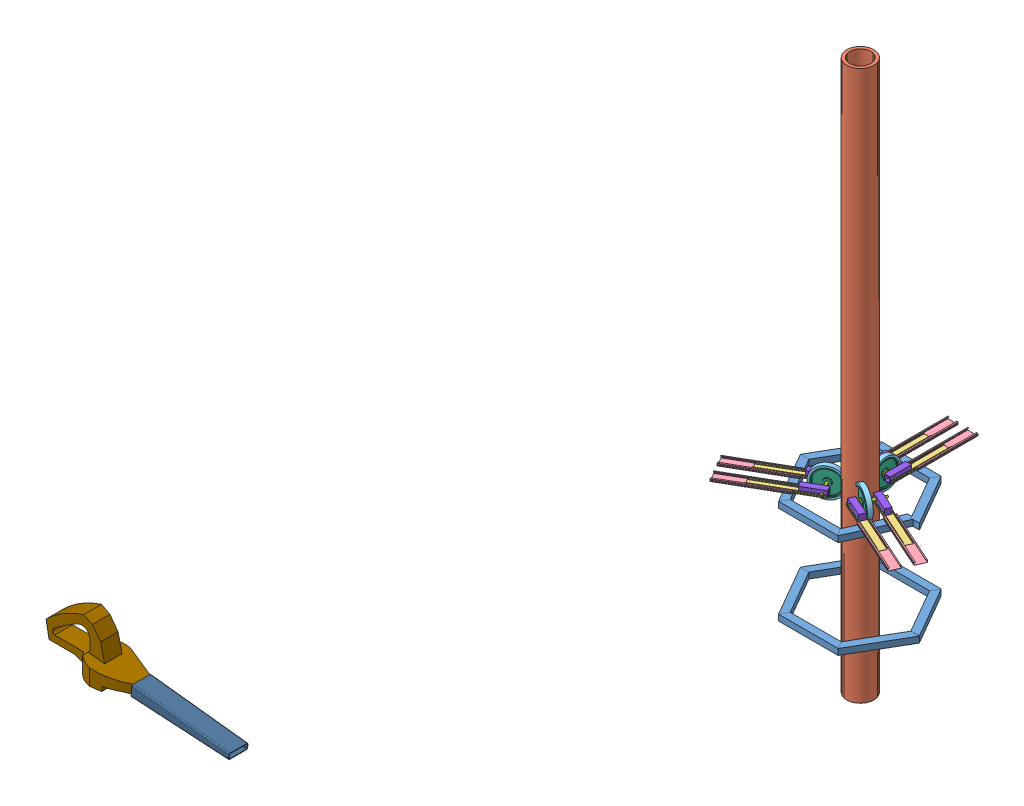
SolidWorks assembly hybrid_new, configuration Default. Lengths in mm.
Overall size (2085.21 2307.62 2779.85).
55 component instances, 10 part files, 44 mates.
Components (placement in the parent):
- Part1-1: Part1 [Default] at (62.7195 89.3412 215.5234) size (250 25.4 31.11)
- Part1-2: Part1 [Default] at (-99.5841 89.3412 82.0449) x (0.5 0 0.866025) z (-0.866025 0 0.5) size (250 25.4 31.11)
- Part1-3: Part1 [Default] at (62.7195 -320.6588 215.5234) size (250 25.4 31.11)
- Part1-4: Part1 [Default] at (250.7642 89.3412 138.3186) x (0.408641 0 -0.912695) z (0.912695 0 0.408641) size (250 25.4 31.11)
- Part1-5: Part1 [Default] at (293.911 -320.6588 -65.5947) x (-0.5 0 -0.866025) z (0.866025 0 -0.5) size (250 25.4 31.11)
- Part1-6: Part1 [Default] at (-65.1402 -320.6588 -125.2534) x (-0.5 0 0.866025) z (-0.866025 0 -0.5) size (250 25.4 31.11)
- Part1-7: Part1 [Default] at (259.7705 -320.6588 141.8405) x (0.503164 0 -0.864191) z (0.864191 0 0.503164) size (250 25.4 31.11)
- Part1-8: Part1 [Default] at (293.911 89.3412 -65.5947) x (-0.5 0 -0.866025) z (0.866025 0 -0.5) size (250 25.4 31.11)
- Part1-9: Part1 [Default] at (131.6074 -320.6588 -199.0732) x (-1 0 0) z (0 0 -1) size (250 25.4 31.11)
- Part1-10: Part1 [Default] at (-65.1402 89.3412 -125.2534) x (-0.5 0 0.866025) z (-0.866025 0 -0.5) size (250 25.4 31.11)
- Part1-11: Part1 [Default] at (131.6074 89.3412 -199.0732) x (-1 0 0) z (0 0 -1) size (250 25.4 31.11)
- Part1-12: Part1 [Default] at (-99.5841 -320.6588 82.0449) x (0.5 0 0.866025) z (-0.866025 0 0.5) size (250 25.4 31.11)
- pole-1: pole [Default] at (101.3065 -621.7615 10.6171) x (-0.949748 0 0.313015) z (-0.313015 0 -0.949748) size (114 2307.62 114)
- wheel_sys-1: wheel_sys [Default] at (-216.3042 -39.4819 -61.3313) x (0 0 -1) z (1 0 0) size (427.17 170.74 131.58)
  - slider-1: slider [Default] at (295.7545 161.9821 248.2331) size (359 10.5 44.88)
    - inner slider-1: inner slider [Default] at (-151.895 -7.559 16.8408) size (254 10.3 34.88)
    - outer slider-1: outer slider [Default] at (-46.895 -7.759 16.5388) size (254 10.08 44.88)
  - wheelwithaxle-1: wheelwithaxle [Default] at (804.7391 46.5563 384.5567) x (0.829197 -0.558957 0) z (-0.558957 -0.829197 0) size (123 127 123)
    - rim-1: rim [Default] at (-711.4248 -76.2879 334.1654) size (123 19 123)
    - centre-1: centre [Default] at (-711.4248 -76.2879 334.1654) size (107 19 107)
    - wheel axle-1: wheel axle [Default] at (-713.6031 -81.7741 334.1654) size (28 127 28)
  - slider-2: slider [Default] at (295.7545 161.9821 330.8673) size (359 10.5 44.88)
    - inner slider-1: inner slider [Default] at (-151.895 -7.559 16.8408) size (254 10.3 34.88)
    - outer slider-1: outer slider [Default] at (-46.895 -7.759 16.5388) size (254 10.08 44.88)
  - support-1: support [Default] at (-18.9561 167.1231 347.1618) x (0 -1 0) z (0 0 1) size (25 90.2 25)
  - support-2: support [Default] at (-18.9561 167.1231 265.119) x (0 -1 0) z (0 0 1) size (25 90.2 25)
- wheel_sys-2: wheel_sys [Default] at (198.0796 -39.4819 322.1299) x (-0.866025 0 0.5) z (-0.5 0 -0.866025) size (427.17 170.74 131.58)
  - slider-1: slider [Default] at (295.7545 161.9821 248.2331) size (359 10.5 44.88)
    - inner slider-1: inner slider [Default] at (-151.895 -7.559 16.8408) size (254 10.3 34.88)
    - outer slider-1: outer slider [Default] at (-46.895 -7.759 16.5388) size (254 10.08 44.88)
  - wheelwithaxle-1: wheelwithaxle [Default] at (804.7391 46.5563 384.5567) x (0.829197 -0.558957 0) z (-0.558957 -0.829197 0) size (123 127 123)
    - rim-1: rim [Default] at (-711.4248 -76.2879 334.1654) size (123 19 123)
    - centre-1: centre [Default] at (-711.4248 -76.2879 334.1654) size (107 19 107)
    - wheel axle-1: wheel axle [Default] at (-713.6031 -81.7741 334.1654) size (28 127 28)
  - slider-2: slider [Default] at (295.7545 161.9821 330.8673) size (359 10.5 44.88)
    - inner slider-1: inner slider [Default] at (-151.895 -7.559 16.8408) size (254 10.3 34.88)
    - outer slider-1: outer slider [Default] at (-46.895 -7.759 16.5388) size (254 10.08 44.88)
  - support-1: support [Default] at (-18.9561 167.1231 347.1618) x (0 -1 0) z (0 0 1) size (25 90.2 25)
  - support-2: support [Default] at (-18.9561 167.1231 265.119) x (0 -1 0) z (0 0 1) size (25 90.2 25)
- wheel_sys-3: wheel_sys [Default] at (268.6929 -39.4819 -238.7978) x (0.912695 0 0.408641) z (-0.408641 0 0.912695) size (427.17 170.74 131.58)
  - slider-1: slider [Default] at (295.7545 161.9821 248.2331) size (359 10.5 44.88)
    - inner slider-1: inner slider [Default] at (-151.895 -7.559 16.8408) size (254 10.3 34.88)
    - outer slider-1: outer slider [Default] at (-46.895 -7.759 16.5388) size (254 10.08 44.88)
  - wheelwithaxle-1: wheelwithaxle [Default] at (804.7391 46.5563 384.5567) x (0.829197 -0.558957 0) z (-0.558957 -0.829197 0) size (123 127 123)
    - rim-1: rim [Default] at (-711.4248 -76.2879 334.1654) size (123 19 123)
    - centre-1: centre [Default] at (-711.4248 -76.2879 334.1654) size (107 19 107)
    - wheel axle-1: wheel axle [Default] at (-713.6031 -81.7741 334.1654) size (28 127 28)
  - slider-2: slider [Default] at (295.7545 161.9821 330.8673) size (359 10.5 44.88)
    - inner slider-1: inner slider [Default] at (-151.895 -7.559 16.8408) size (254 10.3 34.88)
    - outer slider-1: outer slider [Default] at (-46.895 -7.759 16.5388) size (254 10.08 44.88)
  - support-1: support [Default] at (-18.9561 167.1231 347.1618) x (0 -1 0) z (0 0 1) size (25 90.2 25)
  - support-2: support [Default] at (-18.9561 167.1231 265.119) x (0 -1 0) z (0 0 1) size (25 90.2 25)
- blower_assemb-1: blower_assemb [Default] at (-848.1739 35.9897 1900.9403) size (835.33 242.61 170.56)
  - blower-1: blower [Default] at (211.986 78.7515 400.2885) size (835.33 223.79 170.56)
  - nozzle-1: nozzle [Default] at (178.078 64.9806 320.83) x (0.993475 -0.11405 0) z (0 0 1) size (410 47.38 80)
Mates (geometry in assembly coordinates):
- Coincident1: coincident aligned: plane of Part1-2 through (-99.5841 114.7412 82.0449) normal (0 1 0); plane of Part1-4 through (250.7642 114.7412 138.3186) normal (0 1 0)
- Coincident2: coincident aligned: plane of Part1-8 through (293.911 114.7412 -65.5947) normal (0 1 0); plane of Part1-11 through (131.6074 114.7412 -199.0732) normal (0 1 0)
- Coincident3: coincident aligned: plane of Part1-1 through (62.7195 114.7412 215.5234) normal (0 1 0); plane of Part1-10 through (-65.1402 114.7412 -125.2534) normal (0 1 0)
- Coincident4: coincident aligned: plane of Part1-1 through (62.7195 114.7412 215.5234) normal (0 1 0); plane of Part1-4 through (250.7642 114.7412 138.3186) normal (0 1 0)
- Coincident5: coincident aligned: plane of Part1-4 through (250.7642 114.7412 138.3186) normal (0 1 0); plane of Part1-8 through (293.911 114.7412 -65.5947) normal (0 1 0)
- Coincident6: coincident anti-aligned: plane of Part1-8 through (222.1634 114.7412 -208.2813) normal (-0.866025 0 -0.5); plane of Part1-11 through (222.1634 114.7412 -208.2813) normal (0.866025 0 0.5)
- Coincident7: coincident aligned: line of Part1-8 through (222.1634 114.7412 -208.2813) axis (0 -1 0); line of Part1-11 through (222.1634 114.7412 -208.2813) axis (0 -1 0)
- Coincident8: coincident anti-aligned: plane of Part1-10 through (-27.8366 114.7412 -208.2813) normal (0.866025 0 -0.5); plane of Part1-11 through (-27.8366 114.7412 -208.2813) normal (-0.866025 0 0.5)
- Coincident9: coincident aligned: line of Part1-10 through (-27.8366 114.7412 -208.2813) axis (0 -1 0); line of Part1-11 through (-27.8366 114.7412 -208.2813) axis (0 -1 0)
- Coincident10: coincident anti-aligned: plane of Part1-2 through (-152.8366 114.7412 8.2251) normal (0 0 -1); plane of Part1-10 through (-152.8366 114.7412 8.2251) normal (0 0 1)
- Coincident11: coincident aligned: line of Part1-2 through (-152.8366 114.7412 8.2251) axis (0 -1 0); line of Part1-10 through (-152.8366 114.7412 8.2251) axis (0 -1 0)
- Coincident12: coincident anti-aligned: plane of Part1-1 through (-27.8366 114.7412 224.7314) normal (-0.866025 0 -0.5); plane of Part1-2 through (-27.8366 114.7412 224.7314) normal (0.866025 0 0.5)
- Coincident13: coincident aligned: line of Part1-1 through (-27.8366 114.7412 224.7314) axis (0 -1 0); line of Part1-2 through (-27.8366 114.7412 224.7314) axis (0 -1 0)
- Coincident14: coincident aligned: line of Part1-1 through (222.1634 114.7412 224.7314) axis (0 -1 0); line of Part1-4 through (222.1634 114.7412 224.7314) axis (0 -1 0)
- Coincident15: coincident aligned: plane of Part1-3 through (62.7195 -295.2588 215.5234) normal (0 1 0); plane of Part1-7 through (259.7705 -295.2588 141.8405) normal (0 1 0)
- Coincident16: coincident aligned: plane of Part1-6 through (-65.1402 -295.2588 -125.2534) normal (0 1 0); plane of Part1-12 through (-99.5841 -295.2588 82.0449) normal (0 1 0)
- Coincident17: coincident aligned: plane of Part1-5 through (293.911 -295.2588 -65.5947) normal (0 1 0); plane of Part1-9 through (131.6074 -295.2588 -199.0732) normal (0 1 0)
- Coincident18: coincident aligned: plane of Part1-5 through (293.911 -295.2588 -65.5947) normal (0 1 0); plane of Part1-6 through (-65.1402 -295.2588 -125.2534) normal (0 1 0)
- Coincident19: coincident aligned: plane of Part1-3 through (62.7195 -295.2588 215.5234) normal (0 1 0); plane of Part1-6 through (-65.1402 -295.2588 -125.2534) normal (0 1 0)
- Coincident21: coincident anti-aligned: plane of Part1-5 through (222.1634 -295.2588 -208.2813) normal (-0.866025 0 -0.5); plane of Part1-9 through (222.1634 -295.2588 -208.2813) normal (0.866025 0 0.5)
- Coincident22: coincident aligned: line of Part1-5 through (222.1634 -295.2588 -208.2813) axis (0 -1 0); line of Part1-9 through (222.1634 -295.2588 -208.2813) axis (0 -1 0)
- Coincident23: coincident anti-aligned: plane of Part1-6 through (-27.8366 -295.2588 -208.2813) normal (0.866025 0 -0.5); plane of Part1-9 through (-27.8366 -295.2588 -208.2813) normal (-0.866025 0 0.5)
- Coincident24: coincident aligned: line of Part1-6 through (-27.8366 -295.2588 -208.2813) axis (0 -1 0); line of Part1-9 through (-27.8366 -295.2588 -208.2813) axis (0 -1 0)
- Coincident25: coincident anti-aligned: plane of Part1-6 through (-152.8366 -295.2588 8.2251) normal (0 0 1); plane of Part1-12 through (-152.8366 -295.2588 8.2251) normal (0 0 -1)
- Coincident26: coincident aligned: line of Part1-6 through (-152.8366 -295.2588 8.2251) axis (0 -1 0); line of Part1-12 through (-152.8366 -295.2588 8.2251) axis (0 -1 0)
- Coincident27: coincident anti-aligned: plane of Part1-3 through (-27.8366 -295.2588 224.7314) normal (-0.866025 0 -0.5); plane of Part1-12 through (-27.8366 -295.2588 224.7314) normal (0.866025 0 0.5)
- Coincident28: coincident aligned: line of Part1-3 through (-27.8366 -295.2588 224.7314) axis (0 -1 0); line of Part1-12 through (-27.8366 -295.2588 224.7314) axis (0 -1 0)
- Coincident29: coincident aligned: line of Part1-3 through (222.1634 -295.2588 224.7314) axis (0 -1 0); line of Part1-7 through (222.1634 -295.2588 224.7314) axis (0 -1 0)
- Distance3: distance = 410 mm aligned: plane of Part1-1 through (62.7195 114.7412 215.5234) normal (0 1 0); plane of Part1-3 through (62.7195 -295.2588 215.5234) normal (0 1 0)
- Coincident36: coincident aligned: plane of Part1-6 through (-9.8761 -295.2588 -177.1727) normal (0.866025 0 0.5); plane of Part1-10 through (-9.8761 114.7412 -177.1727) normal (0.866025 0 0.5)
- Coincident37: coincident aligned: plane of Part1-9 through (204.2029 -295.2588 -177.1727) normal (0 0 1); plane of Part1-11 through (204.2029 114.7412 -177.1727) normal (0 0 1)
- Perpendicular3: perpendicular: axis of pole-1 through (101.3065 1685.8585 10.6171) axis (0 -1 0); line of assembly
- Distance22: distance = 1685.8585 mm aligned: plane of pole-1 through (101.3065 1685.8585 10.6171) normal (0 1 0); plane of assembly through (0 0 0) normal (0 1 0)
- Coincident82: coincident: axis of pole-1 through (101.3065 1685.8585 10.6171) axis (0 -1 0); plane of assembly
- Coincident87: coincident anti-aligned: plane of Part1-10 through (-65.1402 114.7412 -125.2534) normal (0 1 0); plane of wheel_sys-1/slider-2/outer slider-1 through (131.1019 114.7412 -310.1909) normal (0 -1 0)
- Coincident88: coincident anti-aligned: plane of Part1-11 through (131.6074 114.7412 -199.0732) normal (0 1 0); plane of wheel_sys-2/slider-2/outer slider-1 through (-191.1421 114.7412 145.6972) normal (0 -1 0)
- Coincident89: coincident aligned: plane of Part1-11 through (204.2029 114.7412 -177.1727) normal (0 0 1); plane of wheel_sys-1/slider-1/outer slider-1 through (26.9676 114.9412 -177.1727) normal (0 0 1)
- Coincident90: coincident aligned: plane of Part1-2 through (-116.9155 114.7412 8.2251) normal (0.866025 0 -0.5); plane of wheel_sys-2/slider-1/outer slider-1 through (-23.8779 114.9412 169.371) normal (0.866025 0 -0.5)
- Distance25: distance = 69.765 mm: point of Part1-8; line of wheel_sys-1/slider-2/outer slider-1 through (152.3987 114.9412 -431.1727) axis (0 0 1)
- Distance26: distance = 83.0998 mm: point of Part1-10; line of wheel_sys-2/slider-2/inner slider-1 through (6.5866 114.9412 12.1372) axis (-0.866025 0 0.5)
- Coincident94: coincident aligned: plane of Part1-4 through (201.1102 114.7412 195.6267) normal (-0.912695 0 -0.408641); plane of wheel_sys-3/slider-2/outer slider-1 through (241.2421 114.9412 105.9927) normal (-0.912695 0 -0.408641)
- Coincident95: coincident anti-aligned: plane of Part1-4 through (250.7642 114.7412 138.3186) normal (0 1 0); plane of wheel_sys-3/slider-2/outer slider-1 through (353.8614 114.7412 179.9723) normal (0 -1 0)
- Distance27: distance = 77.8669 mm: point of Part1-4; line of wheel_sys-3/slider-2/inner slider-1 through (129.7574 114.9412 98.0434) axis (0.912695 0 0.408641)
- Coincident96: coincident anti-aligned: plane of Part1-1 through (62.7195 114.7412 215.5234) normal (0 1 0); plane of blower_assemb-1/blower-1 through (-636.1879 114.7412 2301.2288) normal (0 -1 0)
